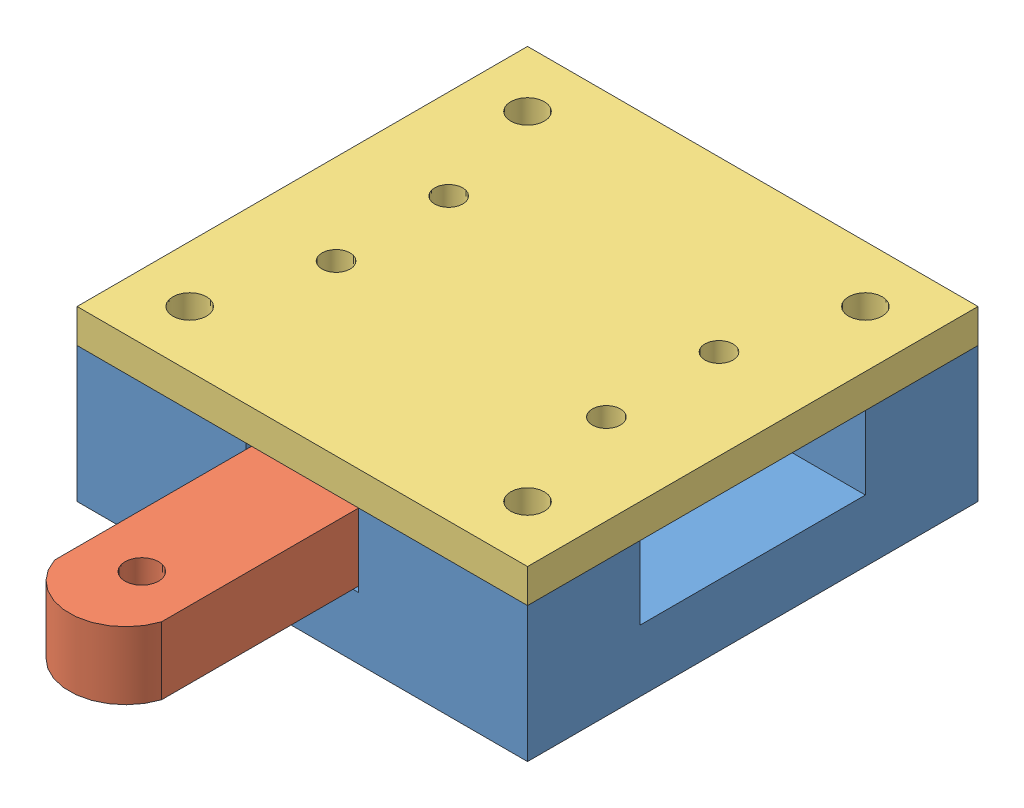
SolidWorks assembly AssemblageJack, configuration Défaut. Lengths in mm.
Overall size (40 15 60.44).
3 component instances, 3 part files, 6 mates.
Components (placement in the parent):
- Support_Jack-1: Support_Jack [Défaut] at (-15.7475 7.4981 -26.0398) size (40 12 40)
- jack-1: jack [Défaut] at (-15.9975 0.9981 15.9602) size (9.5 6 58.44)
- ToitJack-1: ToitJack [Défaut] at (-15.7475 7.4981 -6.0398) x (1 0 0) z (0 1 0) size (40 40 3)
Mates (geometry in assembly coordinates):
- Coaxiale1: concentric anti-aligned: cylinder of Support_Jack-1 through (-30.7475 -4.5029 -21.0398) axis (0 1 0) radius 1.5; cylinder of ToitJack-1 through (-30.7475 10.4981 -21.0398) axis (0 -1 0) radius 1.5
- Coaxiale2: concentric anti-aligned: cylinder of Support_Jack-1 through (-0.7475 -4.5029 8.9602) axis (0 1 0) radius 1.5; cylinder of ToitJack-1 through (-0.7475 10.4981 8.9602) axis (0 -1 0) radius 1.5
- Coïncidente1: coincident anti-aligned: plane of Support_Jack-1 through (-35.7475 7.4981 13.9602) normal (0 1 0); plane of ToitJack-1 through (4.2525 7.4981 -26.0398) normal (0 -1 0)
- Coïncidente2: coincident anti-aligned: plane of Support_Jack-1 through (-10.7475 0.9981 13.9602) normal (0 1 0); plane of jack-1 through (-15.9975 0.9981 29.399) normal (0 -1 0)
- Coïncidente3: coincident anti-aligned: plane of Support_Jack-1 through (-20.7475 0.9981 13.9602) normal (1 0 0); plane of jack-1 through (-20.7475 6.9981 -24.0398) normal (-1 0 0)
- DistanceLimite1: limit distance = 0 mm anti-aligned: plane of Support_Jack-1 through (4.2525 7.4981 -24.0398) normal (0 0 1); plane of jack-1 through (-11.2475 6.9981 -24.0398) normal (0 0 -1)
